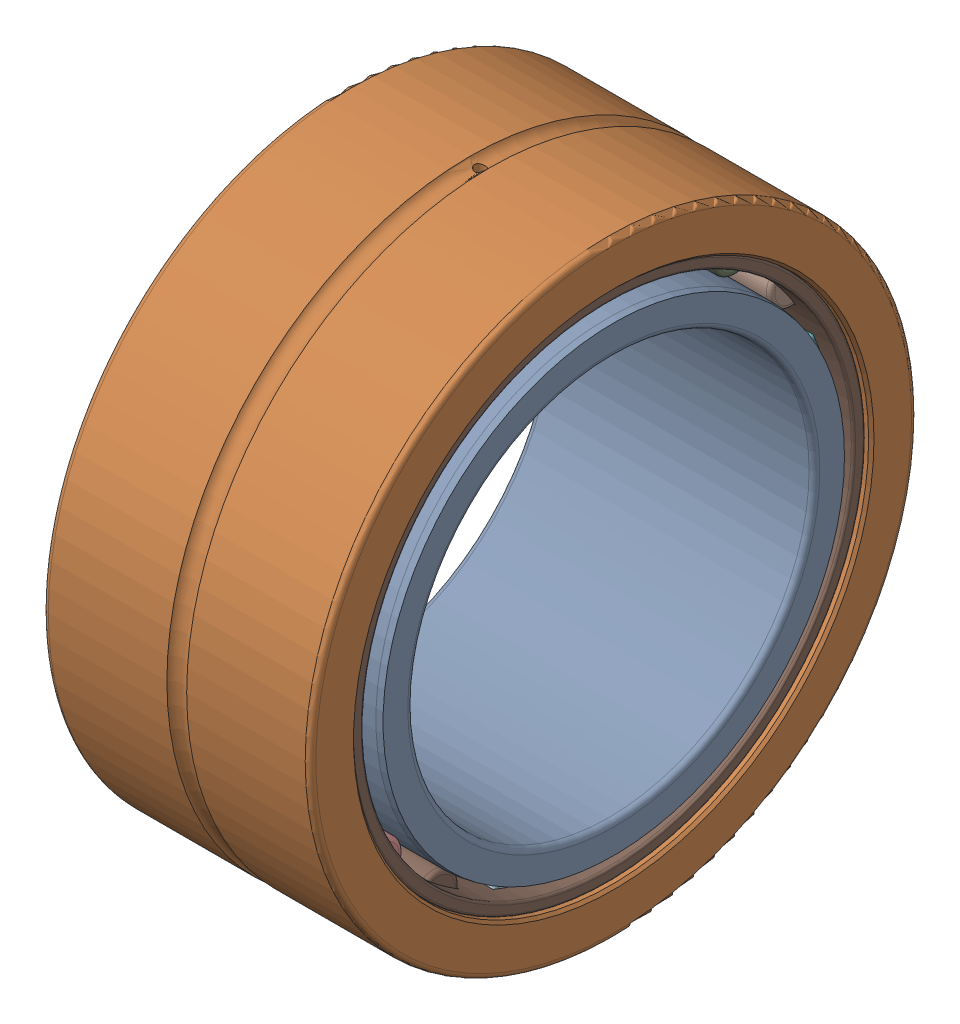
SolidWorks assembly NA5909, configuration Default. Lengths in mm.
Overall size (30 68 68).
23 component instances, 4 part files, 0 mates.
Components (placement in the parent):
- NA5909Inner ring-1: NA5909Inner ring [Default] at origin size (30 52 52)
- NA5909Outer ring-1: NA5909Outer ring [Default] at origin size (30 68 68)
- NA5909 ring-1: NA5909 ring [Default] at (3 28.4 0) size (24 4.8 4.8)
- NA5909 ring-2: NA5909 ring [Default] at (3 27.01 8.7761) size (24 4.8 4.8)
- NA5909 ring-3: NA5909 ring [Default] at (3 22.9761 16.6931) size (24 4.8 4.8)
- NA5909 ring-4: NA5909 ring [Default] at (3 16.6931 22.9761) size (24 4.8 4.8)
- NA5909 ring-5: NA5909 ring [Default] at (3 8.7761 27.01) size (24 4.8 4.8)
- NA5909 ring-6: NA5909 ring [Default] at (3 0 28.4) size (24 4.8 4.8)
- NA5909 ring-7: NA5909 ring [Default] at (3 -8.7761 27.01) size (24 4.8 4.8)
- NA5909 ring-8: NA5909 ring [Default] at (3 -16.6931 22.9761) size (24 4.8 4.8)
- NA5909 ring-9: NA5909 ring [Default] at (3 -22.9761 16.6931) size (24 4.8 4.8)
- NA5909 ring-10: NA5909 ring [Default] at (3 -27.01 8.7761) size (24 4.8 4.8)
- NA5909 ring-11: NA5909 ring [Default] at (3 -28.4 0) size (24 4.8 4.8)
- NA5909 ring-12: NA5909 ring [Default] at (3 -27.01 -8.7761) size (24 4.8 4.8)
- NA5909 ring-13: NA5909 ring [Default] at (3 -22.9761 -16.6931) size (24 4.8 4.8)
- NA5909 ring-14: NA5909 ring [Default] at (3 -16.6931 -22.9761) size (24 4.8 4.8)
- NA5909 ring-15: NA5909 ring [Default] at (3 -8.7761 -27.01) size (24 4.8 4.8)
- NA5909 ring-16: NA5909 ring [Default] at (3 0 -28.4) size (24 4.8 4.8)
- NA5909 ring-17: NA5909 ring [Default] at (3 8.7761 -27.01) size (24 4.8 4.8)
- NA5909 ring-18: NA5909 ring [Default] at (3 16.6931 -22.9761) size (24 4.8 4.8)
- NA5909 ring-19: NA5909 ring [Default] at (3 22.9761 -16.6931) size (24 4.8 4.8)
- NA5909 ring-20: NA5909 ring [Default] at (3 27.01 -8.7761) size (24 4.8 4.8)
- NA5909Cage-1: NA5909Cage [Default] at origin size (28.8 57.66 57.66)
